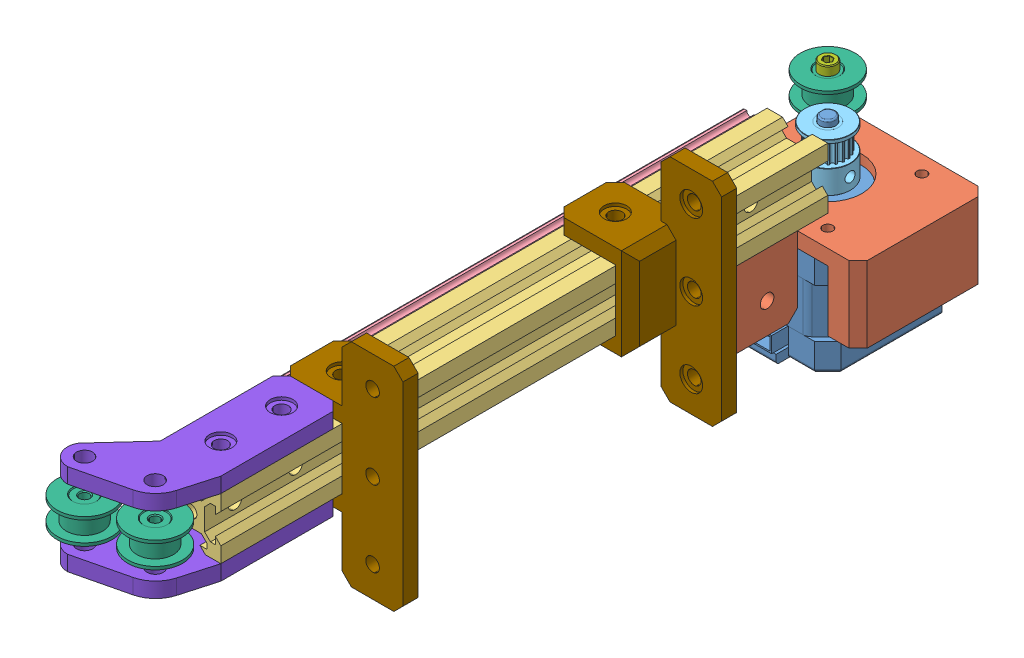
SolidWorks assembly Y_axis_assembly, configuration Default. Lengths in mm.
Overall size (57 83.3 261.67).
13 component instances, 9 part files, 25 mates.
Components (placement in the parent):
- Nema_17-1: Nema_17 [Default] at (33.488 30.381 30.4531) size (42 55.32 47)
- Y_motor_mount-1: Y_motor_mount [Default] at (33.488 38.381 30.4531) size (52.5 25 82.5)
- 200mm_20x20-1: 200mm_20x20 [Default] at (34.738 53.381 141.7031) size (20 20 200)
- 200mm_MGN12_rail-1: 200mm_MGN12_rail [Default] at (20.738 53.381 141.7031) x (0 1 0) z (0 0 1) size (12 8 200)
- GT2_pulley_wheel-1: GT2_pulley_wheel [Výchozí] at (33.488 42.381 30.4531) size (15 16 15)
- Smooth_pulley_wheel-1: Smooth_pulley_wheel [Default] at (17.988 53.631 14.9531) size (18 8.5 18)
- M3x25-1: M3x25 [Default] at (17.988 57.631 14.9531) size (5.6 28 5.6)
- Y_pulley_plate-1: Y_pulley_plate [Default] at (34.738 63.381 241.7031) x (0 0 -1) z (1 0 0) size (62.57 5 33.65)
- Smooth_pulley_wheel-2: Smooth_pulley_wheel [Default] at (35.0906 53.381 253.7031) size (18 8.5 18)
- Smooth_pulley_wheel-3: Smooth_pulley_wheel [Default] at (16.738 53.381 258.6206) size (18 8.5 18)
- Y_axis_stabilizer-1: Y_axis_stabilizer [Default] at (54.738 53.231 201.7031) x (0 1 0) z (-1 0 0) size (70 20 40)
- Y_pulley_plate-2: Y_pulley_plate [Default] at (34.738 38.381 241.7031) x (0 0 -1) z (1 0 0) size (62.57 5 33.65)
- Y_axis_stabilizer-2: Y_axis_stabilizer [Default] at (54.738 53.531 91.7031) x (0 -1 0) z (-1 0 0) size (70 20 40)
Mates (geometry in assembly coordinates):
- Coincident4: coincident anti-aligned: plane of 200mm_20x20-1 through (24.738 43.381 241.7031) normal (-1 0 0); plane of 200mm_MGN12_rail-1 through (24.738 47.381 241.7031) normal (1 0 0)
- Distance1: distance = 4 mm aligned: plane of 200mm_MGN12_rail-1 through (24.738 59.381 241.7031) normal (0 1 0); plane of 200mm_20x20-1 through (24.738 63.381 241.7031) normal (0 1 0)
- Distance2: distance = 32.5 mm aligned: plane of 200mm_20x20-1 through (34.738 53.381 41.7031) normal (0 0 -1); plane of Y_motor_mount-1 through (12.238 43.381 9.2031) normal (0 0 -1)
- Concentric4: concentric aligned: circle of Nema_17-1; circle of GT2_pulley_wheel-1
- Coincident9: coincident anti-aligned: plane of Nema_17-1 through (33.488 42.381 30.4531) normal (0 1 0); plane of GT2_pulley_wheel-1 through (33.488 42.381 30.4531) normal (0 -1 0)
- Concentric5: concentric anti-aligned: cylinder of Y_motor_mount-1 through (17.988 43.381 14.9531) axis (0 -1 0) radius 1.65; cylinder of Smooth_pulley_wheel-1 through (17.988 49.631 14.9531) axis (0 1 0) radius 1.55
- Distance5: distance = 6 mm anti-aligned: plane of Smooth_pulley_wheel-1 through (17.988 49.381 14.9531) normal (0 -1 0); plane of Y_motor_mount-1 through (33.488 43.381 30.4531) normal (0 1 0)
- Concentric6: concentric aligned: cylinder of Smooth_pulley_wheel-1 through (17.988 49.631 14.9531) axis (0 1 0) radius 1.55; cylinder of M3x25-1 through (17.988 50.631 14.9531) axis (0 1 0) radius 1.5
- Coincident14: coincident anti-aligned: plane of Smooth_pulley_wheel-1 through (17.988 57.631 14.9531) normal (0 1 0); plane of M3x25-1 through (17.988 57.631 14.9531) normal (0 -1 0)
- Coincident15: coincident aligned: plane of 200mm_20x20-1 through (24.738 43.381 241.7031) normal (-1 0 0); plane of Y_pulley_plate-1 through (24.738 68.381 241.7031) normal (-1 0 0)
- Coincident16: coincident anti-aligned: plane of 200mm_20x20-1 through (24.738 63.381 241.7031) normal (0 1 0); plane of Y_pulley_plate-1 through (16.738 63.381 258.6206) normal (0 -1 0)
- Coincident19: coincident: plane of 200mm_20x20-1 through (34.738 53.381 241.7031) normal (0 0 1); line of Y_pulley_plate-1 through (24.738 68.381 241.7031) axis (0 -1 0)
- Concentric7: concentric aligned: circle of Y_pulley_plate-1; circle of Smooth_pulley_wheel-2
- Distance6: distance = 5.75 mm anti-aligned: plane of Smooth_pulley_wheel-2 through (35.0906 57.631 253.7031) normal (0 1 0); plane of Y_pulley_plate-1 through (16.738 63.381 258.6206) normal (0 -1 0)
- Concentric8: concentric aligned: circle of Y_pulley_plate-1; circle of Smooth_pulley_wheel-3
- Distance7: distance = 5.75 mm anti-aligned: plane of Smooth_pulley_wheel-3 through (16.738 57.631 258.6206) normal (0 1 0); plane of Y_pulley_plate-1 through (16.738 63.381 258.6206) normal (0 -1 0)
- Coincident20: coincident: plane of 200mm_20x20-1 through (24.738 63.381 241.7031) normal (0 1 0); plane of Frame_stabilizer-1 through (44.738 63.381 91.7031) normal (0 -1 0)
- Coincident21: coincident: plane of Y_motor_mount-1 through (39.738 18.381 91.7031) normal (0 0 1); plane of Frame_stabilizer-1 through (44.738 63.381 91.7031) normal (0 0 1)
- Coincident22: coincident aligned: plane of 200mm_20x20-1 through (44.738 43.381 241.7031) normal (1 0 0); plane of Frame_stabilizer-1 through (44.738 63.381 91.7031) normal (1 0 0)
- Coincident23: coincident anti-aligned: plane of Y_pulley_plate-1 through (24.738 68.381 201.7031) normal (0 0 -1); plane of Frame_stabilizer_2-1 through (54.738 53.231 201.7031) normal (0 0 1)
- Coincident25: coincident anti-aligned: plane of 200mm_20x20-1 through (24.738 63.381 241.7031) normal (0 1 0); plane of Frame_stabilizer_2-1 through (44.738 63.381 181.7031) normal (0 -1 0)
- Coincident26: coincident anti-aligned: plane of 200mm_20x20-1 through (44.738 43.381 241.7031) normal (1 0 0); plane of Frame_stabilizer_2-1 through (44.738 18.231 196.7031) normal (-1 0 0)
- Coincident27: coincident: plane of 200mm_20x20-1 through (44.738 43.381 241.7031) normal (1 0 0); plane of Y_axis_stabilizer-2 through (44.738 88.531 96.7031) normal (-1 0 0)
- Coincident28: coincident: plane of 200mm_20x20-1 through (24.738 43.381 241.7031) normal (0 -1 0); plane of Y_axis_stabilizer-2 through (44.738 43.381 111.7031) normal (0 1 0)
- Coincident29: coincident anti-aligned: plane of Y_motor_mount-1 through (39.738 18.381 91.7031) normal (0 0 1); plane of Y_axis_stabilizer-2 through (54.738 53.531 91.7031) normal (0 0 -1)
